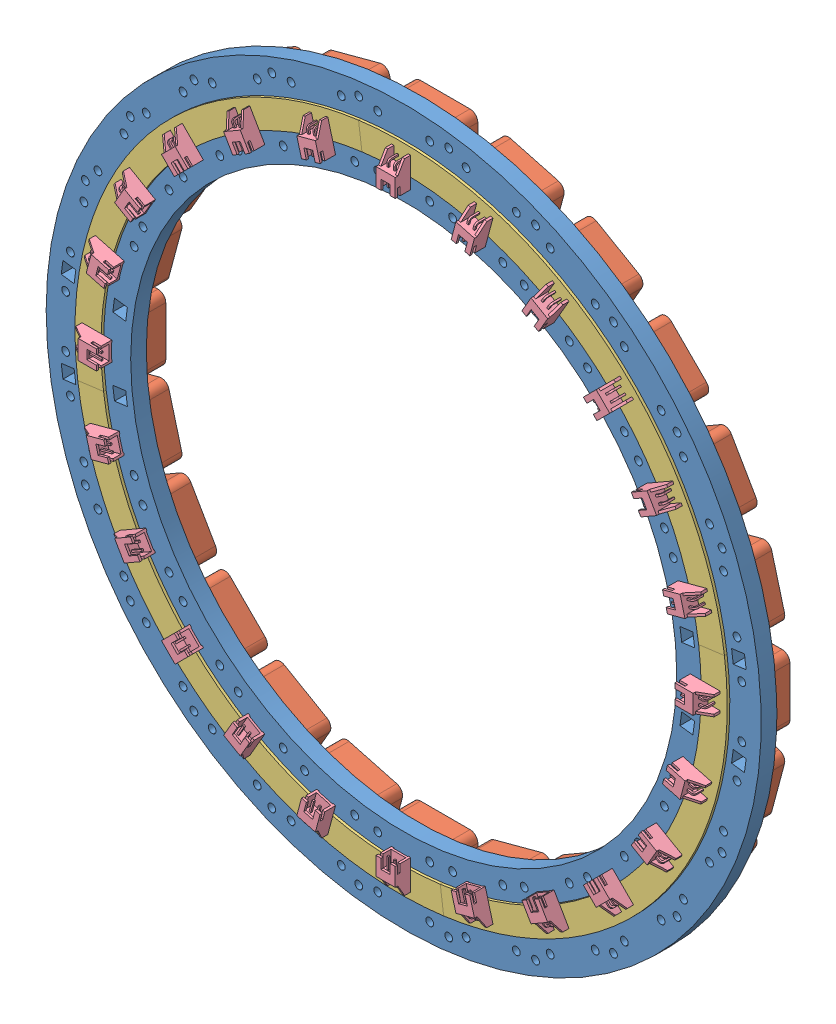
SolidWorks assembly ring_assembly, configuration Default. Lengths in mm.
Overall size (275 275 22.95).
53 component instances, 4 part files, 11 mates.
Components (placement in the parent):
- ring-1: ring [Default] at origin size (275 275 6)
- Fan-1: Fan [Default] at origin size (25 25 10)
- Board^ring_assembly-1: Board^ring_assembly [Default] at (0 0 6) size (140.71 110.35 1) (virtual)
- S2B-XH-A-1: S2B-XH-A [Default] at (0 -116.9631 7) x (-1 0 0) z (0 1 0) size (7.4 5.95 11.5)
- S2B-XH-A-2: S2B-XH-A [Default] at (30.2723 -112.9777 7) x (-0.965926 -0.258819 0) z (-0.258819 0.965926 0) size (7.4 5.95 11.5)
- S2B-XH-A-3: S2B-XH-A [Default] at (58.4815 -101.293 7) x (-0.866025 -0.5 0) z (-0.5 0.866025 0) size (7.4 5.95 11.5)
- S2B-XH-A-4: S2B-XH-A [Default] at (82.7054 -82.7054 7) x (-0.707107 -0.707107 0) z (-0.707107 0.707107 0) size (7.4 5.95 11.5)
- S2B-XH-A-5: S2B-XH-A [Default] at (101.293 -58.4815 7) x (-0.5 -0.866025 0) z (-0.866025 0.5 0) size (7.4 5.95 11.5)
- S2B-XH-A-6: S2B-XH-A [Default] at (112.9777 -30.2723 7) x (-0.258819 -0.965926 0) z (-0.965926 0.258819 0) size (7.4 5.95 11.5)
- S2B-XH-A-7: S2B-XH-A [Default] at (116.9631 0 7) x (0 -1 0) z (-1 0 0) size (7.4 5.95 11.5)
- S2B-XH-A-8: S2B-XH-A [Default] at (112.9777 30.2723 7) x (0.258819 -0.965926 0) z (-0.965926 -0.258819 0) size (7.4 5.95 11.5)
- S2B-XH-A-9: S2B-XH-A [Default] at (101.293 58.4815 7) x (0.5 -0.866025 0) z (-0.866025 -0.5 0) size (7.4 5.95 11.5)
- S2B-XH-A-10: S2B-XH-A [Default] at (82.7054 82.7054 7) x (0.707107 -0.707107 0) z (-0.707107 -0.707107 0) size (7.4 5.95 11.5)
- S2B-XH-A-11: S2B-XH-A [Default] at (58.4815 101.293 7) x (0.866025 -0.5 0) z (-0.5 -0.866025 0) size (7.4 5.95 11.5)
- S2B-XH-A-12: S2B-XH-A [Default] at (30.2723 112.9777 7) x (0.965926 -0.258819 0) z (-0.258819 -0.965926 0) size (7.4 5.95 11.5)
- S2B-XH-A-13: S2B-XH-A [Default] at (0 116.9631 7) x (1 0 0) z (0 -1 0) size (7.4 5.95 11.5)
- S2B-XH-A-14: S2B-XH-A [Default] at (-30.2723 112.9777 7) x (0.965926 0.258819 0) z (0.258819 -0.965926 0) size (7.4 5.95 11.5)
- S2B-XH-A-15: S2B-XH-A [Default] at (-58.4815 101.293 7) x (0.866025 0.5 0) z (0.5 -0.866025 0) size (7.4 5.95 11.5)
- S2B-XH-A-16: S2B-XH-A [Default] at (-82.7054 82.7054 7) x (0.707107 0.707107 0) z (0.707107 -0.707107 0) size (7.4 5.95 11.5)
- S2B-XH-A-17: S2B-XH-A [Default] at (-101.293 58.4815 7) x (0.5 0.866025 0) z (0.866025 -0.5 0) size (7.4 5.95 11.5)
- S2B-XH-A-18: S2B-XH-A [Default] at (-112.9777 30.2723 7) x (0.258819 0.965926 0) z (0.965926 -0.258819 0) size (7.4 5.95 11.5)
- S2B-XH-A-19: S2B-XH-A [Default] at (-116.9631 0 7) x (0 1 0) z (1 0 0) size (7.4 5.95 11.5)
- S2B-XH-A-20: S2B-XH-A [Default] at (-112.9777 -30.2723 7) x (-0.258819 0.965926 0) z (0.965926 0.258819 0) size (7.4 5.95 11.5)
- S2B-XH-A-21: S2B-XH-A [Default] at (-101.293 -58.4815 7) x (-0.5 0.866025 0) z (0.866025 0.5 0) size (7.4 5.95 11.5)
- S2B-XH-A-22: S2B-XH-A [Default] at (-82.7054 -82.7054 7) x (-0.707107 0.707107 0) z (0.707107 0.707107 0) size (7.4 5.95 11.5)
- S2B-XH-A-23: S2B-XH-A [Default] at (-58.4815 -101.293 7) x (-0.866025 0.5 0) z (0.5 0.866025 0) size (7.4 5.95 11.5)
- S2B-XH-A-24: S2B-XH-A [Default] at (-30.2723 -112.9777 7) x (-0.965926 0.258819 0) z (0.258819 0.965926 0) size (7.4 5.95 11.5)
- Fan-2: Fan [Default] x (0.965926 -0.258819 0) z (0 0 1) size (25 25 10)
- Fan-3: Fan [Default] x (0.866025 -0.5 0) z (0 0 1) size (25 25 10)
- Fan-4: Fan [Default] x (0.707107 -0.707107 0) z (0 0 1) size (25 25 10)
- Fan-5: Fan [Default] x (0.5 -0.866025 0) z (0 0 1) size (25 25 10)
- Fan-6: Fan [Default] x (0.258819 -0.965926 0) z (0 0 1) size (25 25 10)
- Fan-7: Fan [Default] x (0 -1 0) z (0 0 1) size (25 25 10)
- Fan-8: Fan [Default] x (-0.258819 -0.965926 0) z (0 0 1) size (25 25 10)
- Fan-9: Fan [Default] x (-0.5 -0.866025 0) z (0 0 1) size (25 25 10)
- Fan-10: Fan [Default] x (-0.707107 -0.707107 0) z (0 0 1) size (25 25 10)
- Fan-11: Fan [Default] x (-0.866025 -0.5 0) z (0 0 1) size (25 25 10)
- Fan-12: Fan [Default] x (-0.965926 -0.258819 0) z (0 0 1) size (25 25 10)
- Fan-13: Fan [Default] x (-1 0 0) z (0 0 1) size (25 25 10)
- Fan-14: Fan [Default] x (-0.965926 0.258819 0) z (0 0 1) size (25 25 10)
- Fan-15: Fan [Default] x (-0.866025 0.5 0) z (0 0 1) size (25 25 10)
- Fan-16: Fan [Default] x (-0.707107 0.707107 0) z (0 0 1) size (25 25 10)
- Fan-17: Fan [Default] x (-0.5 0.866025 0) z (0 0 1) size (25 25 10)
- Fan-18: Fan [Default] x (-0.258819 0.965926 0) z (0 0 1) size (25 25 10)
- Fan-19: Fan [Default] x (0 1 0) z (0 0 1) size (25 25 10)
- Fan-20: Fan [Default] x (0.258819 0.965926 0) z (0 0 1) size (25 25 10)
- Fan-21: Fan [Default] x (0.5 0.866025 0) z (0 0 1) size (25 25 10)
- Fan-22: Fan [Default] x (0.707107 0.707107 0) z (0 0 1) size (25 25 10)
- Fan-23: Fan [Default] x (0.866025 0.5 0) z (0 0 1) size (25 25 10)
- Fan-24: Fan [Default] x (0.965926 0.258819 0) z (0 0 1) size (25 25 10)
- Board^ring_assembly-2: Board^ring_assembly [Default] at (0 0 6) x (0 -1 0) z (0 0 1) size (140.71 110.35 1) (virtual)
- Board^ring_assembly-3: Board^ring_assembly [Default] at (0 0 6) x (-1 0 0) z (0 0 1) size (140.71 110.35 1) (virtual)
- Board^ring_assembly-4: Board^ring_assembly [Default] at (0 0 6) x (0 1 0) z (0 0 1) size (140.71 110.35 1) (virtual)
Mates (geometry in assembly coordinates):
- Coincident5: coincident aligned: plane of ring-1 through (0 0 0) normal (0 0 1); plane of Fan-1 through (0 0 0) normal (0 0 1)
- Coincident6: coincident aligned: plane of ring-1 through (0 0 0) normal (0 1 0); plane of Fan-1 through (0 0 0) normal (0 1 0)
- Coincident7: coincident aligned: plane of ring-1 through (0 0 0) normal (1 0 0); plane of Fan-1 through (0 0 0) normal (1 0 0)
- Coincident8: coincident aligned: plane of ring-1 through (-575.7943 86.7621 6) normal (0 0 1); plane of Board^ring_assembly-1 through (0 0 6) normal (0 0 1)
- Coincident9: coincident aligned: plane of ring-1 through (0 0 0) normal (0 1 0); plane of Board^ring_assembly-1 through (0 0 6) normal (0 1 0)
- Coincident10: coincident aligned: plane of ring-1 through (0 0 0) normal (1 0 0); plane of Board^ring_assembly-1 through (0 0 6) normal (1 0 0)
- Coincident11: coincident anti-aligned: plane of Board^ring_assembly-1 through (0 0 7) normal (0 0 1); plane of S2B-XH-A-1 through (-3.7 -122.7131 7) normal (0 0 -1)
- Parallel1: parallel aligned: plane of Fan-1 through (-9.5 -132.5 -10) normal (0 -1 0); plane of S2B-XH-A-1 through (-3.7 -122.7131 9.3519) normal (0 -1 0)
- Width1: width aligned: plane of Fan-1 through (-12.5 -110.5 -10) normal (-1 0 0); plane of Fan-1 through (12.5 -110.5 -10) normal (1 0 0); plane of S2B-XH-A-1 through (-3.7 -122.7131 7) normal (-1 0 0); plane of S2B-XH-A-1 through (3.7 -122.7131 7) normal (1 0 0)
- Coincident13: coincident: circle of Board^ring_assembly-1; moEndPointRef_w of S2B-XH-A-1
- Coincident15: coordinate: point of ?
